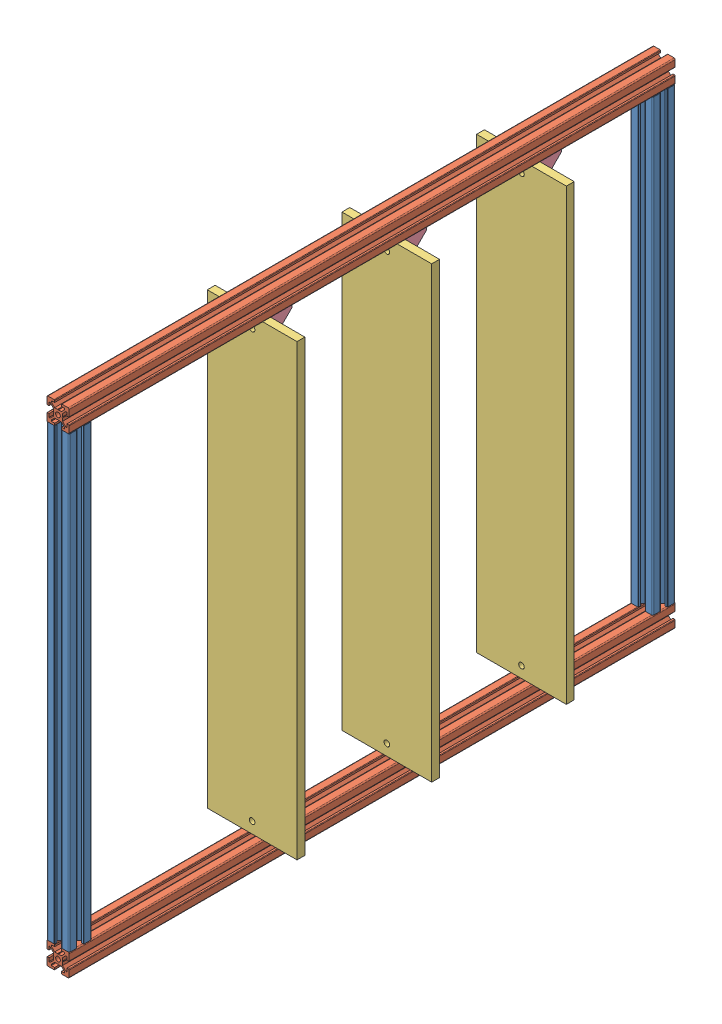
SolidWorks assembly Assieme Campata Magazzino, configuration Default. Lengths in mm.
Overall size (80 440 540).
25 component instances, 6 part files, 18 mates.
Components (placement in the parent):
- Profilato serie 5 20x20x400-2: Profilato serie 5 20x20x400 [Default] at (412.3761 -290.3265 -273.4967) x (0 0 -1) z (0 1 0) size (20 20 400)
- Profilato serie 5 20x20x540-2: Profilato serie 5 20x20x540 [Default] at (412.3761 -300.3265 -283.4967) size (20 20 540)
- Profilato serie 5 20x20x540-3: Profilato serie 5 20x20x540 [Default] at (412.3761 119.6735 256.5033) x (1 0 0) z (0 0 -1) size (20 20 540)
- Profilato serie 5 20x20x400-3: Profilato serie 5 20x20x400 [Default] at (412.3761 109.6735 246.5033) x (0 0 1) z (0 -1 0) size (20 20 400)
- Mensola-1: Mensola [Default] at (372.3761 109.6735 -163.4967) x (0 -1 0) z (-1 0 0) size (400 7 80)
- Staffa 20x20 con alette 90°-2: Staffa 20x20 con alette 90° [Default] at (403.8761 -290.3265 -163.4967) size (17 20 20)
- Staffa 20x20 con alette 90°-3: Staffa 20x20 con alette 90° [Default] at (420.8761 109.6735 -163.4967) x (-1 0 0) z (0 0 1) size (17 20 20)
- Staffa 20x20 con alette 90°-4: Staffa 20x20 con alette 90° [Default] at (420.8761 109.6735 -43.4967) x (-1 0 0) z (0 0 1) size (17 20 20)
- Staffa 20x20 con alette 90°-5: Staffa 20x20 con alette 90° [Default] at (420.8761 109.6735 76.5033) x (-1 0 0) z (0 0 1) size (17 20 20)
- Staffa 20x20 con alette 90°-6: Staffa 20x20 con alette 90° [Default] at (403.8761 -290.3265 -43.4967) size (17 20 20)
- Staffa 20x20 con alette 90°-7: Staffa 20x20 con alette 90° [Default] at (403.8761 -290.3265 76.5033) size (17 20 20)
- Mensola-2: Mensola [Default] at (372.3761 109.6735 -43.4967) x (0 -1 0) z (-1 0 0) size (400 7 80)
- Mensola-3: Mensola [Default] at (372.3761 109.6735 76.5033) x (0 -1 0) z (-1 0 0) size (400 7 80)
- socket button head screw_iso-5: socket button head screw_iso [ISO 7380 - M4 x 8 - 8S] at (412.3761 -285.1265 -174.9517) x (0 -1 0) z (0 0 1) size (10.2 7.6 7.6)
- socket button head screw_iso-6: socket button head screw_iso [ISO 7380 - M4 x 8 - 8S] at (412.3761 104.4735 -174.9517) x (0 1 0) z (0 0 1) size (10.2 7.6 7.6)
- socket button head screw_iso-7: socket button head screw_iso [ISO 7380 - M4 x 8 - 8S] at (412.3761 -285.1265 -54.9517) x (0 -1 0) z (0 0 1) size (10.2 7.6 7.6)
- socket button head screw_iso-8: socket button head screw_iso [ISO 7380 - M4 x 8 - 8S] at (412.3761 -285.1265 65.0483) x (0 -1 0) z (0 0 1) size (10.2 7.6 7.6)
- socket button head screw_iso-9: socket button head screw_iso [ISO 7380 - M4 x 8 - 8S] at (412.3761 104.4735 -54.9517) x (0 1 0) z (0 0 1) size (10.2 7.6 7.6)
- socket button head screw_iso-10: socket button head screw_iso [ISO 7380 - M4 x 8 - 8S] at (412.3761 104.4735 65.0483) x (0 1 0) z (0 0 1) size (10.2 7.6 7.6)
- pan head cross recess screw_din-3: pan head cross recess screw_din [DIN EN ISO 7045 - M5 x 8 - Z - 8S] at (412.3761 99.7184 -170.1967) x (0 0 1) z (-1 0 0) size (6.63 9.5 9.5)
- pan head cross recess screw_din-4: pan head cross recess screw_din [DIN EN ISO 7045 - M5 x 8 - Z - 8S] at (412.3761 -280.3714 -170.1967) x (0 0 1) z (-1 0 0) size (6.63 9.5 9.5)
- pan head cross recess screw_din-5: pan head cross recess screw_din [DIN EN ISO 7045 - M5 x 8 - Z - 8S] at (412.3761 -280.3714 -50.1967) x (0 0 1) z (-1 0 0) size (6.63 9.5 9.5)
- pan head cross recess screw_din-6: pan head cross recess screw_din [DIN EN ISO 7045 - M5 x 8 - Z - 8S] at (412.3761 -280.3714 69.8033) x (0 0 1) z (-1 0 0) size (6.63 9.5 9.5)
- pan head cross recess screw_din-7: pan head cross recess screw_din [DIN EN ISO 7045 - M5 x 8 - Z - 8S] at (412.3761 99.7184 -50.1967) x (0 0 1) z (-1 0 0) size (6.63 9.5 9.5)
- pan head cross recess screw_din-8: pan head cross recess screw_din [DIN EN ISO 7045 - M5 x 8 - Z - 8S] at (412.3761 99.7184 69.8033) x (0 0 1) z (-1 0 0) size (6.63 9.5 9.5)
Mates (geometry in assembly coordinates):
- Coincidente4: coincident anti-aligned: plane of Profilato serie 5 20x20x400-2 through (415.8761 -290.3265 -263.9967) normal (0 -1 0); plane of Profilato serie 5 20x20x540-2 through (415.8761 -290.3265 256.5033) normal (0 1 0)
- Coincidente5: coincident aligned: plane of Profilato serie 5 20x20x400-2 through (422.3761 109.6735 -269.9967) normal (1 0 0); plane of Profilato serie 5 20x20x540-2 through (422.3761 -296.8265 256.5033) normal (1 0 0)
- Coincidente6: coincident aligned: plane of Profilato serie 5 20x20x400-2 through (415.8761 109.6735 -283.4967) normal (0 0 -1); plane of Profilato serie 5 20x20x540-2 through (402.8761 -303.8265 -283.4967) normal (0 0 -1)
- Parallelo1: parallel anti-aligned: plane of Profilato serie 5 20x20x400-2 through (408.8761 109.6735 -263.4967) normal (0 0 1); plane of Mensola-1 through (372.3761 109.6735 -163.4967) normal (0 0 -1)
- Coincidente12: coincident anti-aligned: plane of Profilato serie 5 20x20x540-2 through (408.8761 -290.3265 256.5033) normal (0 1 0); plane of Mensola-1 through (372.3761 -290.3265 -156.4967) normal (0 -1 0)
- Distanza2: distance = 120 mm aligned: plane of Mensola-1 through (372.3761 109.6735 -163.4967) normal (0 0 -1); plane of Profilato serie 5 20x20x400-2 through (408.8761 109.6735 -283.4967) normal (0 0 -1)
- Coincidente13: coincident anti-aligned: plane of Mensola-1 through (372.3761 109.6735 -163.4967) normal (0 0 -1); plane of Staffa 20x20 con alette 90°-2 through (420.8761 -270.8265 -163.4967) normal (0 0 1)
- Coincidente15: coincident anti-aligned: plane of Profilato serie 5 20x20x540-2 through (415.8761 -290.3265 256.5033) normal (0 1 0); plane of Staffa 20x20 con alette 90°-2 through (420.8761 -290.3265 -163.9967) normal (0 -1 0)
- Distanza3: distance = 30 mm aligned: plane of Profilato serie 5 20x20x540-2 through (402.3761 -296.8265 256.5033) normal (-1 0 0); plane of Mensola-1 through (372.3761 109.6735 -156.4967) normal (-1 0 0)
- Distanza4: distance = 1.5 mm aligned: plane of Staffa 20x20 con alette 90°-2 through (420.8761 -289.8265 -182.9967) normal (1 0 0); plane of Profilato serie 5 20x20x540-2 through (422.3761 -296.8265 256.5033) normal (1 0 0)
- Concentrico8: concentric aligned: cylinder of Staffa 20x20 con alette 90°-2 through (412.3761 -290.3265 -174.9517) axis (0 1 0) radius 3; cylinder of socket button head screw_iso-5 through (412.3761 -285.1265 -174.9517) axis (0 1 0) radius 3.8
- Coincidente25: coincident anti-aligned: plane of Staffa 20x20 con alette 90°-2 through (417.8761 -287.3265 -166.4967) normal (0 1 0); plane of socket button head screw_iso-5 through (414.3761 -287.3265 -174.9517) normal (0 -1 0)
- Concentrico9: concentric aligned: cylinder of Staffa 20x20 con alette 90°-3 through (412.3761 109.6735 -174.9517) axis (0 -1 0) radius 3; cylinder of socket button head screw_iso-6 through (412.3761 104.4735 -174.9517) axis (0 -1 0) radius 3.8
- Coincidente26: coincident anti-aligned: plane of Staffa 20x20 con alette 90°-3 through (406.8761 106.6735 -166.4967) normal (0 -1 0); plane of socket button head screw_iso-6 through (410.3761 106.6735 -174.9517) normal (0 1 0)
- Concentrico13: concentric aligned: cylinder of Mensola-1 through (412.3761 99.7184 -153.4967) axis (0 0 -1) radius 2.5; cylinder of pan head cross recess screw_din-3 through (412.3761 99.7184 -195.5967) axis (0 0 -1) radius 4.75
- Concentrico14: concentric aligned: cylinder of Mensola-1 through (412.3761 -280.3714 -153.4967) axis (0 0 -1) radius 2.5; cylinder of pan head cross recess screw_din-4 through (412.3761 -280.3714 -195.5967) axis (0 0 -1) radius 4.75
- Coincidente28: coincident anti-aligned: plane of Staffa 20x20 con alette 90°-2 through (403.8761 -290.3265 -166.4967) normal (0 0 -1); plane of pan head cross recess screw_din-4 through (412.3761 -277.8714 -166.4967) normal (0 0 1)
- Coincidente29: coincident anti-aligned: plane of Staffa 20x20 con alette 90°-3 through (420.8761 109.6735 -166.4967) normal (0 0 -1); plane of pan head cross recess screw_din-3 through (412.3761 102.2184 -166.4967) normal (0 0 1)
